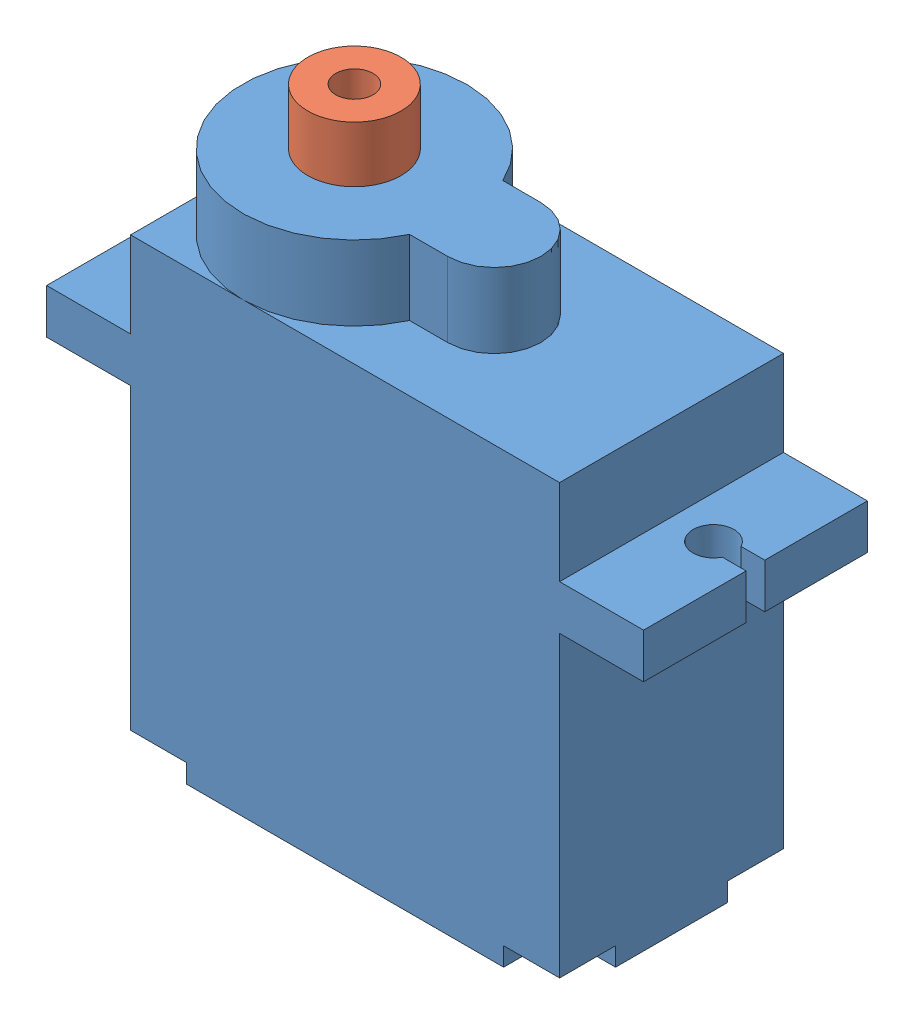
SolidWorks assembly assembly, configuration Varsayılan. Lengths in mm.
Overall size (32 31 12).
2 component instances, 2 part files, 2 mates.
Components (placement in the parent):
- body-1: body [Varsayılan] at (-117.2872 -12.0692 0) size (32 28 12)
- gear-1: gear [Varsayılan] at (-122.7872 18.9308 0) x (0.982136 0 -0.188173) z (0 -1 0) size (5 5 3)
Mates (geometry in assembly coordinates):
- Eş Merkezli1: concentric: cylinder of body-1 through (-122.7872 15.9308 0) axis (0 -1 0) radius 6; cylinder of gear-1 through (-122.7872 15.9308 0) axis (0 1 0) radius 2.5
- Çakışık1: coincident anti-aligned: plane of body-1 through (-115.2872 15.9308 0) normal (0 1 0); plane of gear-1 through (-122.7872 15.9308 0) normal (0 -1 0)
